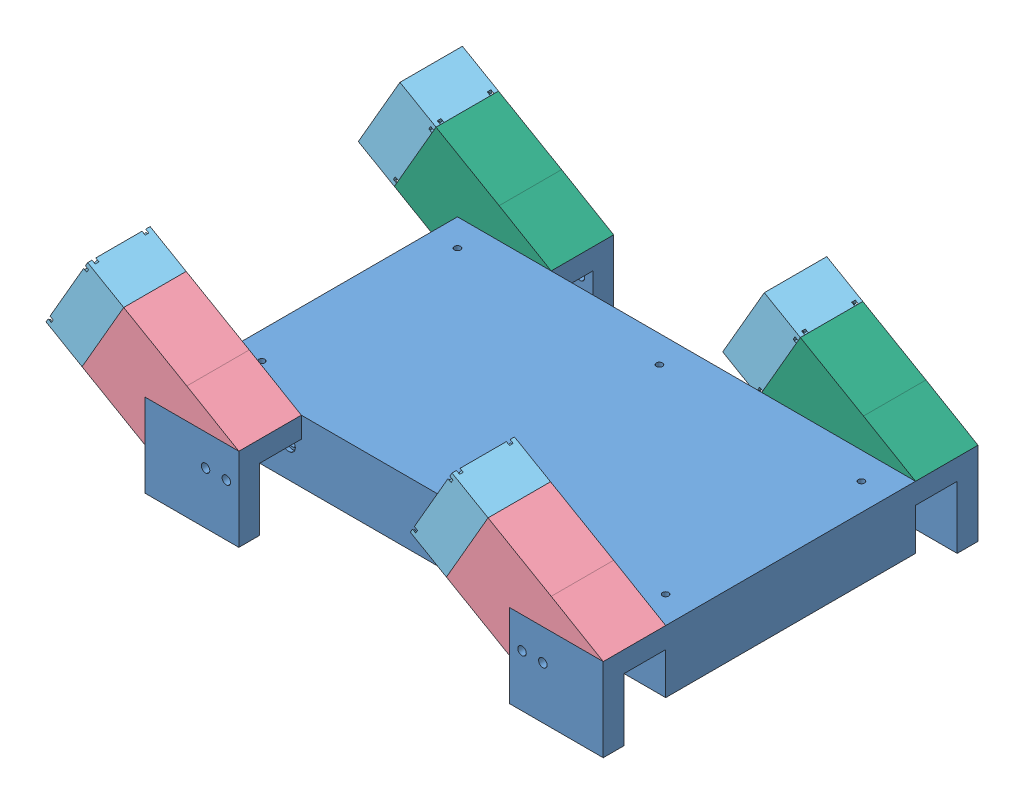
SolidWorks assembly DriveBed, configuration Default. Lengths in mm.
Overall size (340.01 110.67 228.6).
72 component instances, 24 part files, 20 mates.
Components (placement in the parent):
- DriveBed-1: DriveBed [Default] at (50.4754 133.5108 217.4162) size (279.4 57.15 228.6)
- 393-4: 393 [Default] at (6.9577 171.6019 247.7332) x (-1 0 0) z (0 -1 0) size (56.4 55.81 25)
  - SPPM206-0150BO-1: SPPM206-0150BO [Default] at (-10.5 -23.5 9.5) x (-1 0 0) z (0 0 1) size (3.3 16.36 3.3)
  - SPPM206-0150BO-2: SPPM206-0150BO [Default] at (-10.5 -23.5 -9.5) x (-1 0 0) z (0 0 1) size (3.3 16.36 3.3)
  - SPPM204-0050BO-1: SPPM204-0050BO [Default] at (0 -6.45 -6.2) size (3.3 6.41 3.3)
  - 276-2177-002 Rev1-1: 276-2177-002 Rev1 [Default] at origin size (50 27.05 25)
  - SPPM206-0150BO-3: SPPM206-0150BO [Default] at (33.5 -23.5 -9.5) x (-1 0 0) z (0 0 1) size (3.3 16.36 3.3)
  - 276-2177-008 Rev1-1: 276-2177-008 Rev1 [Default] at (25.7 -19.25 0) x (-0.086075 0 -0.996289) z (0 -1 0) size (16.7 16.7 17.5)
  - 276-2177-010 Rev1-1: 276-2177-010 Rev1 [Default] at (24.2 -4.9 0) x (0 1 0) z (0.653198 0 -0.757187) size (20.8 2 2)
  - 276-2177-001 Rev1-1: 276-2177-001 Rev1 [Default] at origin size (50 7.01 25)
  - 276-2177-012 Rev1-1: 276-2177-012 Rev1 [Default] at (25.7 -19.1 0) x (-0.525336 0 0.850895) z (0 1 0) size (6 6 2.85)
  - 276-2177-018 Rev1-1: 276-2177-018 Rev1 [Default] at (-12 2.1 0) x (0 0 -1) z (1 0 0) size (6.82 4.47 8.9)
  - 276-2177-014 Rev1-1: 276-2177-014 Rev1 [Default] at (-11.6 -15 0) x (0 1 0) z (0 0 1) size (1 18.4 20.4)
  - 276-2177-019 Rev1-1: 276-2177-019 Rev1 [Default] at (0.3 -33 0) x (-0.999228 0 0.03928) z (0.03928 0 0.999228) size (6.3 15.8 6.3)
  - SPPM206-0150BO-4: SPPM206-0150BO [Default] at (33.5 -2.5 -9.5) x (-0.585444 0 0.810713) z (-0.810713 0 -0.585444) size (3.3 16.36 3.3)
  - 276-2177-004 Rev1-1: 276-2177-004 Rev1 [Default] at (0 2.3 0) x (-0.521464 0 -0.853273) z (0 -1 0) size (5.83 5.83 4.5)
  - SPPM206-0150BO-5: SPPM206-0150BO [Default] at (33.5 -2.5 9.5) size (3.3 16.36 3.3)
  - 276-2177-019 Rev1-2: 276-2177-019 Rev1 [Default] at (13 -33 0) x (0.158525 0 -0.987355) z (-0.987355 0 -0.158525) size (6.3 15.8 6.3)
  - SPPM204-0050BO-2: SPPM204-0050BO [Default] at (0 -6.45 6.2) size (3.3 6.41 3.3)
  - FS130-FT-21100-1: FS130-FT-21100 [Default] at (0 -15 0) x (0 0 -1) z (0 1 0) size (20.4 15.4 34.7)
  - 276-2177-006 Rev1-1: 276-2177-006 Rev1 [Default] at (24.2 -0.95 0) x (-0.999044 0 -0.043716) z (0 -1 0) size (20.25 20.26 13)
  - 276-2177-009 Rev1-1: 276-2177-009 Rev1 [Default] at (15.1 -17.75 0) x (1 0 0) z (0 -1 0) size (2 2 27.5)
  - 276-2177-011 Rev1-1: 276-2177-011 Rev1 [Default] at (12.1 -0.9 0) x (0 1 0) z (-0.101873 0 0.994797) size (14.8 2 2)
  - 276-2177-007 Rev1_276-2177-007a-1: 276-2177-007 Rev1_276-2177-007a [Default] at (15.1 -10.55 0) x (0.26937 0 -0.963037) z (0 -1 0) size (14.01 14.03 13)
  - 276-2177-013 Rev1-1: 276-2177-013 Rev1 [Default] at (25.7 -31.5 0) x (-1 0 0) z (0 1 0) size (10 10 10.05)
  - SPPM206-0150BO-6: SPPM206-0150BO [Default] at (-10.5 -2.5 9.5) x (0.055695 0 -0.998448) z (0.998448 0 0.055695) size (3.3 16.36 3.3)
  - 276-2177-003 Rev1-1: 276-2177-003 Rev1 [Default] at (0 -25 0) size (48.69 26 23.69)
  - SPPM206-0150BO-7: SPPM206-0150BO [Default] at (-10.5 -2.5 -9.5) size (3.3 16.36 3.3)
  - 276-2177-005 Rev1-1: 276-2177-005 Rev1 [Default] at (12.1 2.15 0) x (-0.981818 0 0.189823) z (0 -1 0) size (19.95 19.95 7)
  - SPPM206-0150BO-8: SPPM206-0150BO [Default] at (33.5 -23.5 9.5) x (-1 0 0) z (0 0 1) size (3.3 16.36 3.3)
- 393-5: 393 [Default] at (6.9577 171.6019 216.7052) x (-1 0 0) z (0 1 0) size (56.4 55.81 25)
  - SPPM206-0150BO-1: SPPM206-0150BO [Default] at (-10.5 -23.5 9.5) x (-1 0 0) z (0 0 1) size (3.3 16.36 3.3)
  - SPPM206-0150BO-2: SPPM206-0150BO [Default] at (-10.5 -23.5 -9.5) x (-1 0 0) z (0 0 1) size (3.3 16.36 3.3)
  - SPPM204-0050BO-1: SPPM204-0050BO [Default] at (0 -6.45 -6.2) size (3.3 6.41 3.3)
  - 276-2177-002 Rev1-1: 276-2177-002 Rev1 [Default] at origin size (50 27.05 25)
  - SPPM206-0150BO-3: SPPM206-0150BO [Default] at (33.5 -23.5 -9.5) x (-1 0 0) z (0 0 1) size (3.3 16.36 3.3)
  - 276-2177-008 Rev1-1: 276-2177-008 Rev1 [Default] at (25.7 -19.25 0) x (-0.086075 0 -0.996289) z (0 -1 0) size (16.7 16.7 17.5)
  - 276-2177-010 Rev1-1: 276-2177-010 Rev1 [Default] at (24.2 -4.9 0) x (0 1 0) z (0.653198 0 -0.757187) size (20.8 2 2)
  - 276-2177-001 Rev1-1: 276-2177-001 Rev1 [Default] at origin size (50 7.01 25)
  - 276-2177-012 Rev1-1: 276-2177-012 Rev1 [Default] at (25.7 -19.1 0) x (-0.525336 0 0.850895) z (0 1 0) size (6 6 2.85)
  - 276-2177-018 Rev1-1: 276-2177-018 Rev1 [Default] at (-12 2.1 0) x (0 0 -1) z (1 0 0) size (6.82 4.47 8.9)
  - 276-2177-014 Rev1-1: 276-2177-014 Rev1 [Default] at (-11.6 -15 0) x (0 1 0) z (0 0 1) size (1 18.4 20.4)
  - 276-2177-019 Rev1-1: 276-2177-019 Rev1 [Default] at (0.3 -33 0) x (-0.999228 0 0.03928) z (0.03928 0 0.999228) size (6.3 15.8 6.3)
  - SPPM206-0150BO-4: SPPM206-0150BO [Default] at (33.5 -2.5 -9.5) x (-0.585444 0 0.810713) z (-0.810713 0 -0.585444) size (3.3 16.36 3.3)
  - 276-2177-004 Rev1-1: 276-2177-004 Rev1 [Default] at (0 2.3 0) x (-0.521464 0 -0.853273) z (0 -1 0) size (5.83 5.83 4.5)
  - SPPM206-0150BO-5: SPPM206-0150BO [Default] at (33.5 -2.5 9.5) size (3.3 16.36 3.3)
  - 276-2177-019 Rev1-2: 276-2177-019 Rev1 [Default] at (13 -33 0) x (0.158525 0 -0.987355) z (-0.987355 0 -0.158525) size (6.3 15.8 6.3)
  - SPPM204-0050BO-2: SPPM204-0050BO [Default] at (0 -6.45 6.2) size (3.3 6.41 3.3)
  - FS130-FT-21100-1: FS130-FT-21100 [Default] at (0 -15 0) x (0 0 -1) z (0 1 0) size (20.4 15.4 34.7)
  - 276-2177-006 Rev1-1: 276-2177-006 Rev1 [Default] at (24.2 -0.95 0) x (-0.999044 0 -0.043716) z (0 -1 0) size (20.25 20.26 13)
  - 276-2177-009 Rev1-1: 276-2177-009 Rev1 [Default] at (15.1 -17.75 0) x (1 0 0) z (0 -1 0) size (2 2 27.5)
  - 276-2177-011 Rev1-1: 276-2177-011 Rev1 [Default] at (12.1 -0.9 0) x (0 1 0) z (-0.101873 0 0.994797) size (14.8 2 2)
  - 276-2177-007 Rev1_276-2177-007a-1: 276-2177-007 Rev1_276-2177-007a [Default] at (15.1 -10.55 0) x (0.26937 0 -0.963037) z (0 -1 0) size (14.01 14.03 13)
  - 276-2177-013 Rev1-1: 276-2177-013 Rev1 [Default] at (25.7 -31.5 0) x (-1 0 0) z (0 1 0) size (10 10 10.05)
  - SPPM206-0150BO-6: SPPM206-0150BO [Default] at (-10.5 -2.5 9.5) x (0.055695 0 -0.998448) z (0.998448 0 0.055695) size (3.3 16.36 3.3)
  - 276-2177-003 Rev1-1: 276-2177-003 Rev1 [Default] at (0 -25 0) size (48.69 26 23.69)
  - SPPM206-0150BO-7: SPPM206-0150BO [Default] at (-10.5 -2.5 -9.5) size (3.3 16.36 3.3)
  - 276-2177-005 Rev1-1: 276-2177-005 Rev1 [Default] at (12.1 2.15 0) x (-0.981818 0 0.189823) z (0 -1 0) size (19.95 19.95 7)
  - SPPM206-0150BO-8: SPPM206-0150BO [Default] at (33.5 -23.5 9.5) x (-1 0 0) z (0 0 1) size (3.3 16.36 3.3)
- ShaftCollar-1: ShaftCollar [Default] at (-4.7723 150.3977 129.8572) x (0.999903 -0.013903 0) z (0 0 1) size (11 11.03 6.6)
- Nacelle Assembly-3: Nacelle Assembly [Default] at (-71.8702 192.688 384.7185) x (-0.866025 0.5 0) z (0 0 -1) size (106.64 50.8 38.1)
  - Calf Nacelle-1: Calf Nacelle [Default] at (1.6936 15.1916 38.1993) size (81.24 50.8 38.1)
  - MotorEndcap-1: MotorEndcap [Default] at (5.6235 2.2988 24.7342) x (0 0 -1) z (1 0 0) size (38.1 50.8 25.4)
- Nacelle Assembly-7: Nacelle Assembly [Default] at (150.3798 192.688 384.7185) x (-0.866025 0.5 0) z (0 0 -1) size (106.64 50.8 38.1)
  - Calf Nacelle-1: Calf Nacelle [Default] at (1.6936 15.1916 38.1993) size (81.24 50.8 38.1)
  - MotorEndcap-1: MotorEndcap [Default] at (5.6235 2.2988 24.7342) x (0 0 -1) z (1 0 0) size (38.1 50.8 25.4)
- MirrorNacelle Assembly-10: MirrorNacelle Assembly [Default] at (150.3798 192.688 79.7199) x (-0.866025 0.5 0) z (0 0 -1) size (106.64 50.8 38.1)
  - MirrorCalf Nacelle-1: MirrorCalf Nacelle [Default] at (1.6936 15.1916 -38.1993) size (81.24 50.8 38.1)
  - MotorEndcap-1: MotorEndcap [Default] at (31.0235 2.2988 -24.7342) x (0 0 1) z (-1 0 0) size (38.1 50.8 25.4)
- MirrorNacelle Assembly1-10: MirrorNacelle Assembly1 [Default] at (-71.8702 192.688 79.7199) x (-0.866025 0.5 0) z (0 0 -1) size (106.64 50.8 38.1)
  - MirrorCalf Nacelle-1: MirrorCalf Nacelle [Default] at (1.6936 15.1916 -38.1993) size (81.24 50.8 38.1)
  - MotorEndcap-1: MotorEndcap [Default] at (31.0235 2.2988 -24.7342) x (0 0 1) z (-1 0 0) size (38.1 50.8 25.4)
Mates (geometry in assembly coordinates):
- Concentric3: concentric aligned: circle of DriveBed-1; circle of 393-4/276-2177-003 Rev1-1
- Concentric4: concentric aligned: circle of DriveBed-1; circle of 393-4/276-2177-003 Rev1-1
- Coincident2: coincident anti-aligned: plane of DriveBed-1 through (143.18 133.5108 280.7332) normal (0 0 -1); plane of 393-4/276-2177-003 Rev1-1 through (6.9577 171.6019 280.7332) normal (0 0 1)
- Concentric5: concentric aligned: cylinder of ShaftCollar-1 through (-4.7723 150.3977 126.5552) axis (0 0 1) radius 5.5; unknown of DriveBed-1
- Parallel4: parallel anti-aligned: line of DriveBed-1 through (14.2777 190.6608 346.5192) axis (0 0 -1); line of ? through (14.2777 190.6608 308.4192) axis (0 0 1)
- Distance5: distance = 0 mm: line of ? through (-42.8723 190.6608 308.4192) axis (0 0 1); line of DriveBed-1 through (-42.8723 190.6608 117.9192) axis (0 0 1)
- Parallel5: parallel anti-aligned: plane of DriveBed-1 through (50.4754 190.6608 217.4162) normal (0 1 0); plane of ? through (14.2777 190.6608 308.4192) normal (0 -1 0)
- Distance6: distance = 0 mm aligned: plane of ? through (14.2777 190.6608 346.5192) normal (0 0 1); plane of DriveBed-1 through (143.18 133.5108 346.5192) normal (0 0 1)
- Distance7: distance = 0 mm: line of ? through (236.5277 190.6608 346.5192) axis (0 0 -1); line of DriveBed-1 through (236.5277 190.6608 346.5192) axis (0 0 -1)
- Distance8: distance = 0 mm: line of ? through (179.3777 190.6608 346.5192) axis (0 0 -1); line of DriveBed-1 through (179.3777 190.6608 346.5192) axis (0 0 -1)
- Distance9: distance = 0 mm aligned: plane of ? through (179.3777 190.6608 346.5192) normal (0 0 1); plane of DriveBed-1 through (50.4754 133.5108 346.5192) normal (0 0 1)
- Distance15: distance = 0 mm: line of Nacelle Assembly-7/Calf Nacelle-1 through (179.3777 165.2608 308.4192) axis (0 0 1); plane of DriveBed-1 through (179.3777 190.6608 346.5192) normal (-1 0 0)
- Distance16: distance = 0 mm aligned: plane of Nacelle Assembly-7/Calf Nacelle-1 through (156.5089 206.6911 346.5192) normal (0 0 1); plane of DriveBed-1 through (50.4754 133.5108 346.5192) normal (0 0 1)
- Parallel12: parallel: plane of DriveBed-1 through (179.3777 190.6608 346.5192) normal (-1 0 0); line of Nacelle Assembly-7/Calf Nacelle-1 through (179.3777 165.2608 308.4192) axis (0 0 1)
- Distance17: distance = 25.4 mm: line of Nacelle Assembly-7/Calf Nacelle-1 through (179.3777 165.2608 308.4192) axis (0 0 1); line of DriveBed-1 through (179.3777 190.6608 346.5192) axis (0 0 -1)
- Distance19: distance = 0 mm: plane of DriveBed-1 through (-42.8723 184.3108 168.7192) normal (-1 0 0); line of Nacelle Assembly-3/Calf Nacelle-1 through (-42.8723 165.2608 308.4192) axis (0 0 1)
- Distance18: distance = 0 mm aligned: plane of Nacelle Assembly-3/Calf Nacelle-1 through (-65.7411 206.6911 346.5192) normal (0 0 1); plane of DriveBed-1 through (143.18 133.5108 346.5192) normal (0 0 1)
- Distance20: distance = 25.4 mm: line of Nacelle Assembly-3/Calf Nacelle-1 through (-42.8723 165.2608 308.4192) axis (0 0 1); line of DriveBed-1 through (-42.8723 190.6608 117.9192) axis (0 0 1)
- Parallel14: parallel aligned: line of DriveBed-1 through (179.3777 190.6608 346.5192) axis (0 -1 0); line of Nacelle Assembly-7/Calf Nacelle-1 through (179.3777 190.6608 346.5192) axis (0 -1 0)
- Parallel15: parallel aligned: line of DriveBed-1 through (-42.8723 190.6608 346.5192) axis (0 -1 0); line of Nacelle Assembly-3/Calf Nacelle-1 through (-42.8723 190.6608 346.5192) axis (0 -1 0)
